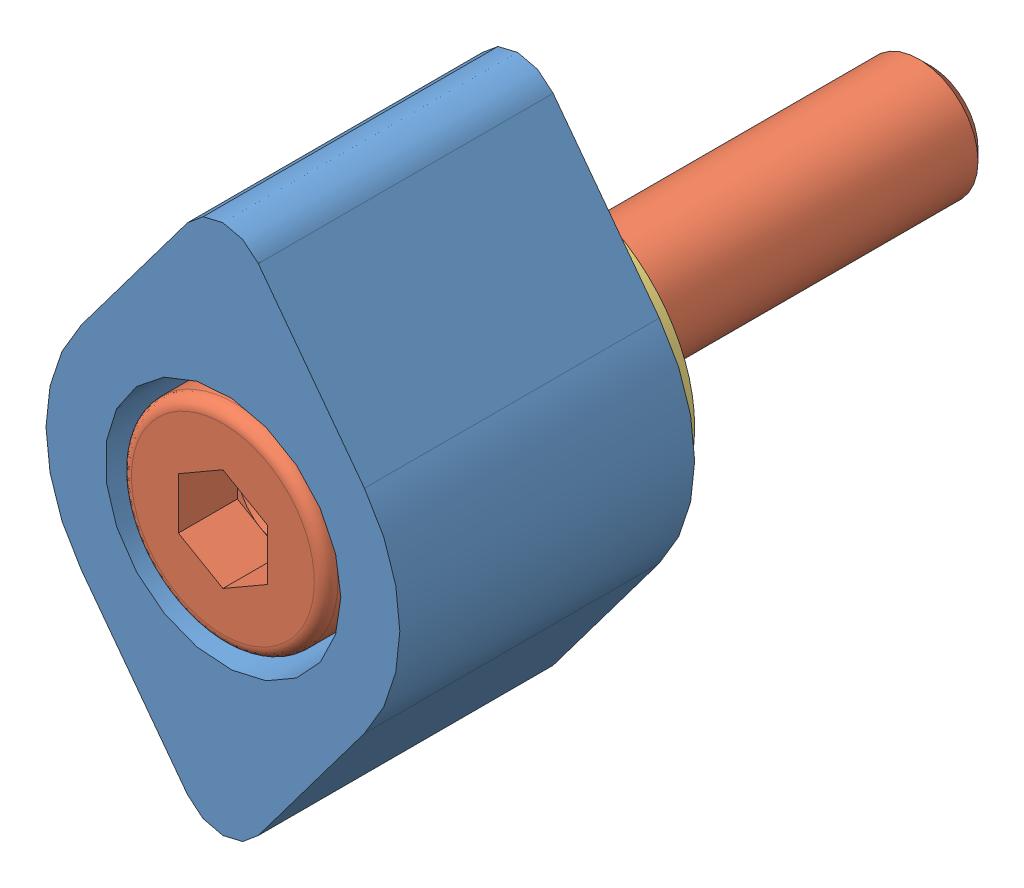
SolidWorks assembly thumb_flag_screw, configuration По умолчанию. Lengths in mm.
Overall size (12 18 24).
3 component instances, 3 part files, 4 mates.
Components (placement in the parent):
- thumb_flag-1: thumb_flag [По умолчанию] at (-71.4451 35.3578 31.093) size (12 18 10)
- socket head cap screw_din-1: socket head cap screw_din [DIN 912 M4 x 20 --- 20N] at (-71.4451 35.3578 41.093) x (0 0 -1) z (1 0 0) size (24 7 7)
- plain washer 6902 type abc_din-1: plain washer 6902 type abc_din [DIN 6902-A4.55] at (-71.4451 35.3578 31.093) x (0 0 -1) z (1 0 0) size (1 10 10)
Mates (geometry in assembly coordinates):
- Концентричный1: concentric aligned: cylinder of thumb_flag-1 through (-71.4451 35.3578 37.093) axis (0 0 1) radius 1.65; cylinder of socket head cap screw_din-1 through (-71.4451 35.3578 72.843) axis (0 0 1) radius 3.5
- Совпадение1: coincident anti-aligned: plane of thumb_flag-1 through (-71.4451 35.3578 37.093) normal (0 0 1); plane of socket head cap screw_din-1 through (-71.4451 38.8578 37.093) normal (0 0 -1)
- Концентричный2: concentric aligned: cylinder of socket head cap screw_din-1 through (-71.4451 35.3578 72.843) axis (0 0 1) radius 2; cylinder of plain washer 6902 type abc_din-1 through (-71.4451 35.3578 30.093) axis (0 0 1) radius 2.275
- Совпадение2: coincident anti-aligned: plane of thumb_flag-1 through (-71.4451 35.3578 31.093) normal (0 0 -1); plane of plain washer 6902 type abc_din-1 through (-71.4451 35.3578 31.093) normal (0 0 1)
